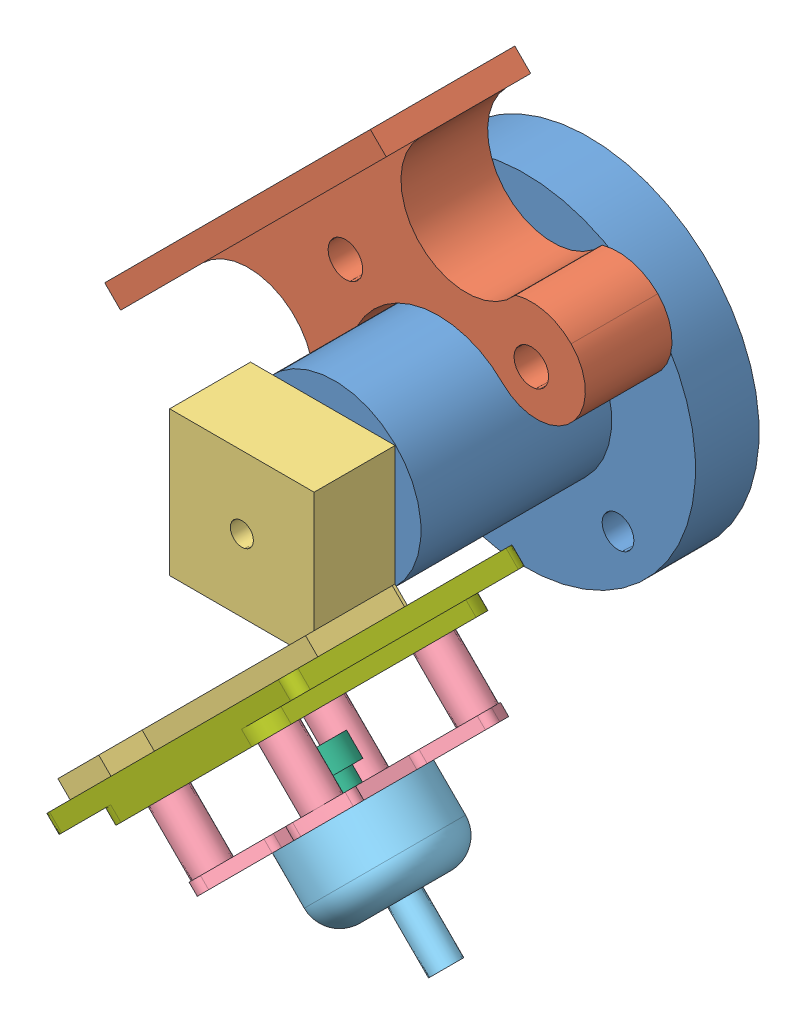
SolidWorks assembly 两轴力传感器装配体, configuration 默认. Lengths in mm.
Overall size (106.81 106.81 107.12).
8 component instances, 7 part files, 10 mates.
Components (placement in the parent):
- 半法兰扭距传感器-2: 半法兰扭距传感器 [默认] at (-1.1059 -0.7953 -46) x (0 1 0) z (1 0 0) size (59 56 59)
- 力传感器固定件-1: 力传感器固定件 [默认] at (-22.2005 42.3083 -10) x (0.707107 0.707107 0) z (0 0 -1) size (65 43.38 25)
- 力矩传感器_电机固定座_连接件-1: 力矩传感器_电机固定座_连接件 [默认] at (-1.1059 -0.7953 0) x (-1 0 0) z (0 0 1) size (39.4 46.21 35.04)
- 电机_固定座_装配体-2: 电机_固定座_装配体 [默认] at (-16.3404 4.5786 12.7308) x (-0.5 -0.5 -0.707107) z (0.707107 -0.707107 0) size (70.71 70.71 40.8)
  - B2212电机固定-1: B2212电机固定 [默认] at (-10.0704 -0.2098 48.25) size (44 44 12.5)
  - 1804无刷电机-1: 1804无刷电机 [默认] at (-10.0704 -0.2098 50.25) size (22.8 22.8 24.3)
  - 磁铁安装件-1: 磁铁安装件 [默认] at (-10.0704 -0.2098 45.75) x (-0.755076 -0.655637 0) z (0 0 -1) size (8 8 8)
  - 底座-1: 底座 [默认] at (26.698 26.7503 35.25) x (0.707107 0.707107 0) z (0 0 1) size (40 60 5.5)
Mates (geometry in assembly coordinates):
- 同心1: concentric: circle of assembly; circle of assembly; circle of 半法兰扭距传感器-2; circle of 力传感器固定件-1
- 重合7: coincident: plane of assembly; plane of assembly; plane of 半法兰扭距传感器-2 through (-7.3559 -7.0453 10) normal (0 -1 0); plane of 力矩传感器_电机固定座_连接件-1 through (-7.3559 -7.0453 0) normal (0 1 0)
- 重合15: coincident: plane of assembly; plane of assembly; plane of 半法兰扭距传感器-2 through (-1.1059 -0.7953 -35) normal (0 0 1); plane of 力传感器固定件-1 through (-22.2005 42.3083 -35) normal (0 0 -1)
- 同心5: concentric: circle of assembly; circle of assembly; circle of 半法兰扭距传感器-2; circle of 力传感器固定件-1
- 平行7: parallel: plane of assembly; plane of assembly; plane of 力传感器固定件-1 through (-48.8356 0.9724 -35) normal (-0.707107 0.707107 0); plane of 电机_固定座_装配体-2/底座-1 through (6.4899 -18.1995 -25.0628) normal (-0.707107 0.707107 0)
- 同心6: concentric: circle of assembly; circle of assembly; circle of 半法兰扭距传感器-2; circle of 力矩传感器_电机固定座_连接件-1
- 重合23: coincident: plane of assembly; plane of assembly; plane of 半法兰扭距传感器-2 through (-1.1059 -0.7953 10) normal (0 0 1); plane of 力矩传感器_电机固定座_连接件-1 through (-1.1059 -0.7953 10) normal (0 0 -1)
- 重合24: coincident: plane of assembly; plane of assembly; plane of 力矩传感器_电机固定座_连接件-1 through (11.3941 -13.2953 0) normal (0.707107 -0.707107 0); plane of 电机_固定座_装配体-2/底座-1 through (6.4899 -18.1995 -25.0628) normal (-0.707107 0.707107 0)
- 重合25: coincident: plane of assembly; line of assembly; plane of 力矩传感器_电机固定座_连接件-1 through (-1.1059 -0.7953 0) normal (0.707107 0.707107 0); line of 电机_固定座_装配体-2/底座-1 through (15.2831 -17.1844 0) axis (0 0 1)
- 重合29: coincident: plane of assembly; plane of assembly; plane of 力矩传感器_电机固定座_连接件-1 through (-1.1059 -0.7953 0) normal (0 0 -1); plane of 电机_固定座_装配体-2/底座-1 through (29.4253 -3.0423 0) normal (0 0 -1)
